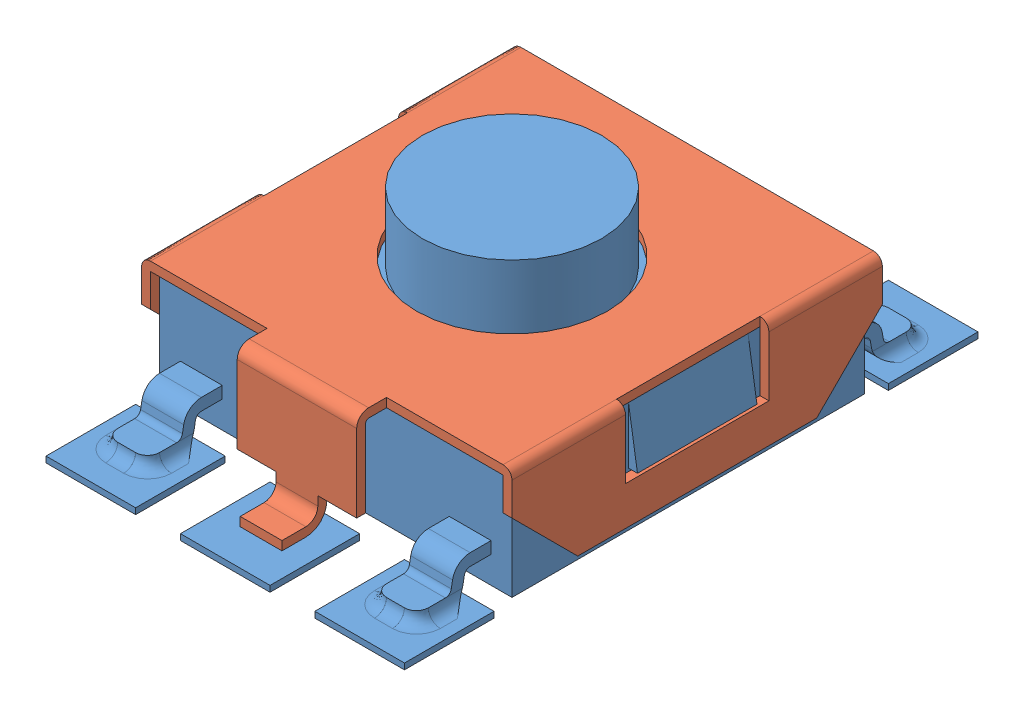
SolidWorks assembly RESET BUTTON, configuration Default. Lengths in mm.
Overall size (6.2 3.1 9.6).
2 component instances, 2 part files, 6 mates.
Components (placement in the parent):
- RESET CORE-1: RESET CORE [Default] at (0 0.1 0) x (-1 0 0) z (0 0 -1) size (6.2 3.1 9.6)
- RESET-1: RESET [Default] at (0 0.1 0) x (0 0 1) z (-1 0 0) size (7.3 2 6.2)
Mates (geometry in assembly coordinates):
- Coincident4: coincident anti-aligned: plane of RESET CORE-1 through (0 0.1 0) normal (0 0 -1); plane of assembly through (0 0 0) normal (0 0 1)
- Coincident5: coincident anti-aligned: plane of RESET CORE-1 through (0 0.1 0) normal (-1 0 0); plane of assembly through (0 0 0) normal (1 0 0)
- Coincident6: coincident anti-aligned: plane of RESET CORE-1 through (0 0 0) normal (0 -1 0); plane of assembly through (0 0 0) normal (0 1 0)
- Coincident7: coincident: plane of RESET-1 through (0 0.1 0) normal (0 0 1); plane of assembly through (0 0 0) normal (0 0 1)
- Coincident9: coincident anti-aligned: plane of RESET-1 through (0 0.1 0) normal (-1 0 0); plane of assembly
- Coincident10: coincident aligned: plane of RESET CORE-1; plane of RESET-1
